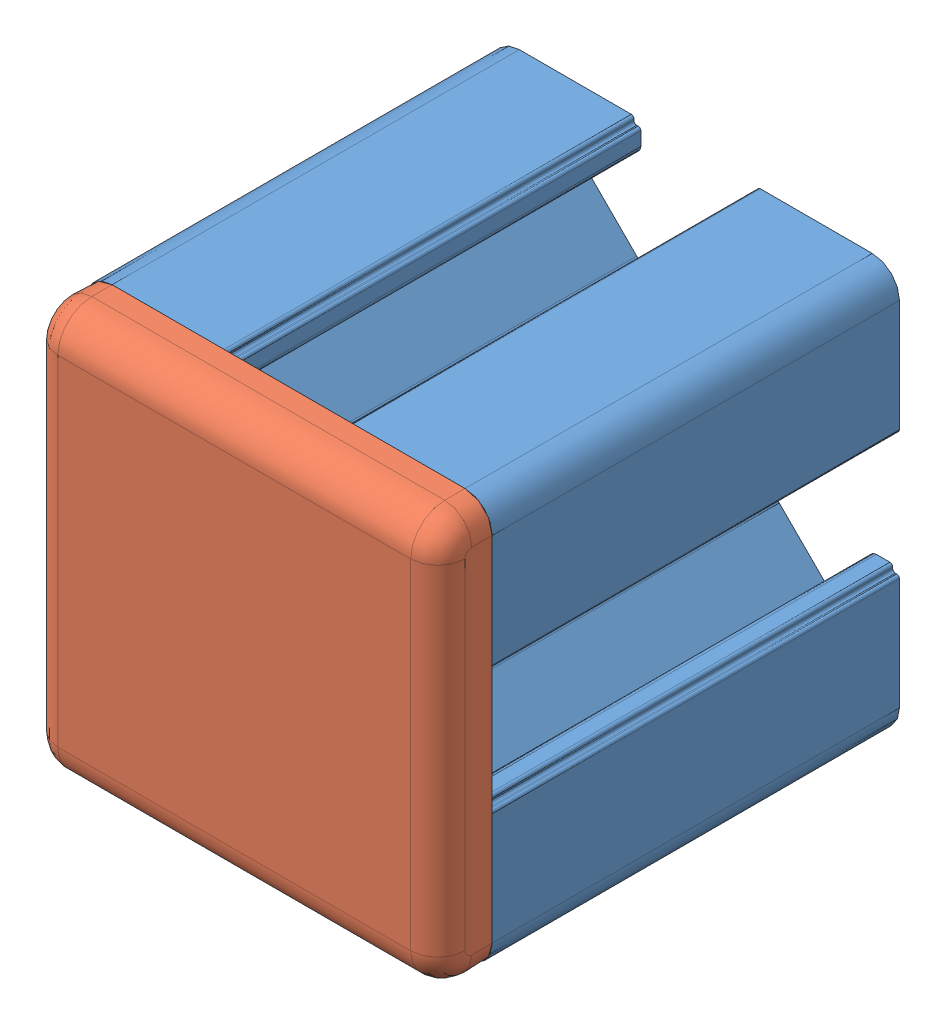
SolidWorks assembly Заглушка30х30СБ, configuration По умолчанию. Lengths in mm.
Overall size (30 30 34).
2 component instances, 2 part files, 6 mates.
Components (placement in the parent):
- 30х30 заглушка-1: 30х30 заглушка [По умолчанию] at origin size (30 30 30)
- Заглушка торцевая 30х30-1: Заглушка торцевая 30х30 [По умолчанию] at (0 0 32) x (0 0 -1) z (1 0 0) size (12 30 30)
Mates (geometry in assembly coordinates):
- Совпадение2: coincident: point of 30х30 заглушка-1
- Параллельность1: parallel anti-aligned: plane of 30х30 заглушка-1 through (0 -15 30) normal (0 -1 0)
- Совпадение4: coincident anti-aligned: plane of 30х30 заглушка-1 through (0 0 0) normal (0 0 -1)
- Совпадение5: coincident anti-aligned: plane of 30х30 заглушка-1 through (0 0 30) normal (0 0 1); plane of Заглушка торцевая 30х30-1 through (-15 -15 30) normal (0 0 -1)
- Совпадение6: coincident aligned: plane of 30х30 заглушка-1 through (0 15 30) normal (0 1 0); plane of Заглушка торцевая 30х30-1 through (-15 15 31.5) normal (0 1 0)
- Совпадение7: coincident aligned: plane of 30х30 заглушка-1 through (15 0 30) normal (1 0 0); plane of Заглушка торцевая 30х30-1 through (15 12.5 31.5) normal (1 0 0)
